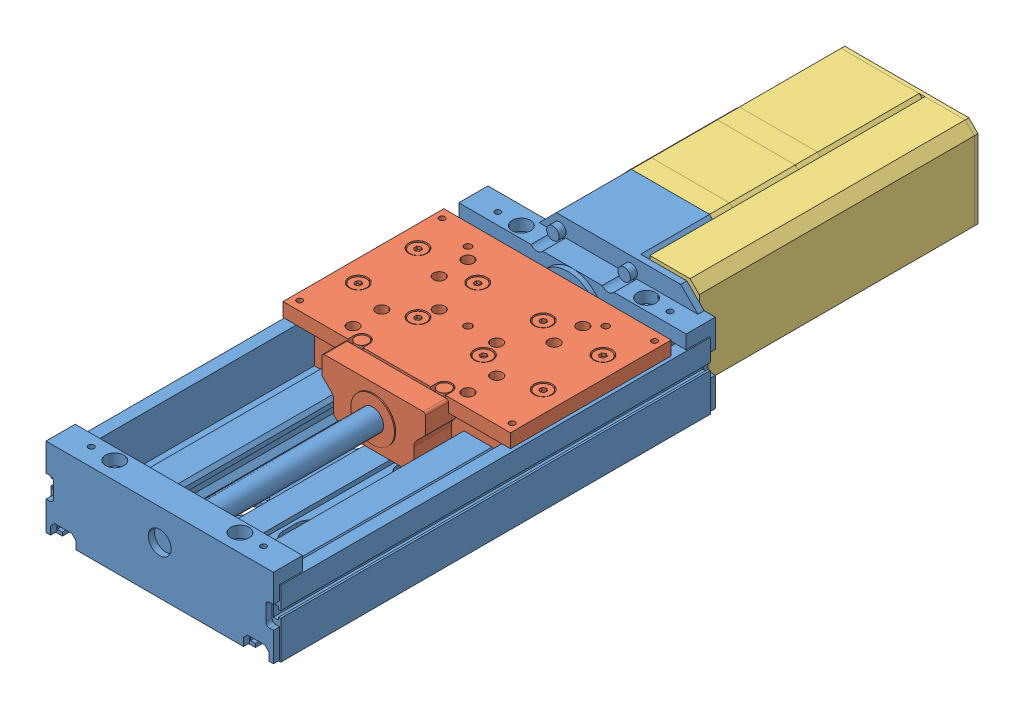
SolidWorks assembly LRQ, configuration LRQ075xL-T3A. Lengths in mm.
Overall size (100 42.5 320.01).
3 component instances, 3 part files, 8 mates.
Components (placement in the parent):
- LRQ_base^LRQ-1: LRQ_base^LRQ [LRQ075L] at origin size (100 42.5 222.4) (virtual)
- LRQ_carriage^LRQ-1: LRQ_carriage^LRQ [LRQ] at origin size (99 26.5 80.5) (virtual)
- NMS17_motor^LRQ-1: NMS17_motor^LRQ [LRQ-T3A] at (0 0 -32.7) size (62 42 126.11) (virtual)
Mates (geometry in assembly coordinates):
- Coincident1: coincident anti-aligned: plane of LRQ_base^LRQ-1 through (0 0 -32.7) normal (0 0 -1); plane of NMS17_motor^LRQ-1 through (0 0 -32.7) normal (0 0 1)
- Coincident2: coincident aligned: plane of NMS17_motor^LRQ-1 through (0 0 -32.7) normal (0 1 0); plane of assembly through (0 0 0) normal (0 1 0)
- Coincident3: coincident aligned: plane of NMS17_motor^LRQ-1 through (0 0 -32.7) normal (1 0 0); plane of assembly through (0 0 0) normal (1 0 0)
- Coincident4: coincident anti-aligned: plane of LRQ_base^LRQ-1 through (-15.5 15.5 10) normal (0 0 1); plane of NMS17_motor^LRQ-1 through (-73 0 10) normal (0 0 -1)
- Concentric1: concentric: cylinder of LRQ_base^LRQ-1 through (-73 0 71.1903) axis (0 0 -1) radius 11; point of NMS17_motor^LRQ-1
- Coincident6: coincident aligned: plane of LRQ_carriage^LRQ-1 through (0 0 0) normal (1 0 0); plane of assembly through (0 0 0) normal (1 0 0)
- Coincident7: coincident aligned: plane of LRQ_carriage^LRQ-1 through (0 0 0) normal (0 1 0); plane of assembly through (0 0 0) normal (0 1 0)
- LimitDistance1: limit distance = 0 mm aligned: plane of assembly through (0 0 0) normal (0 0 1); plane of LRQ_carriage^LRQ-1 through (0 0 0) normal (0 0 1)
